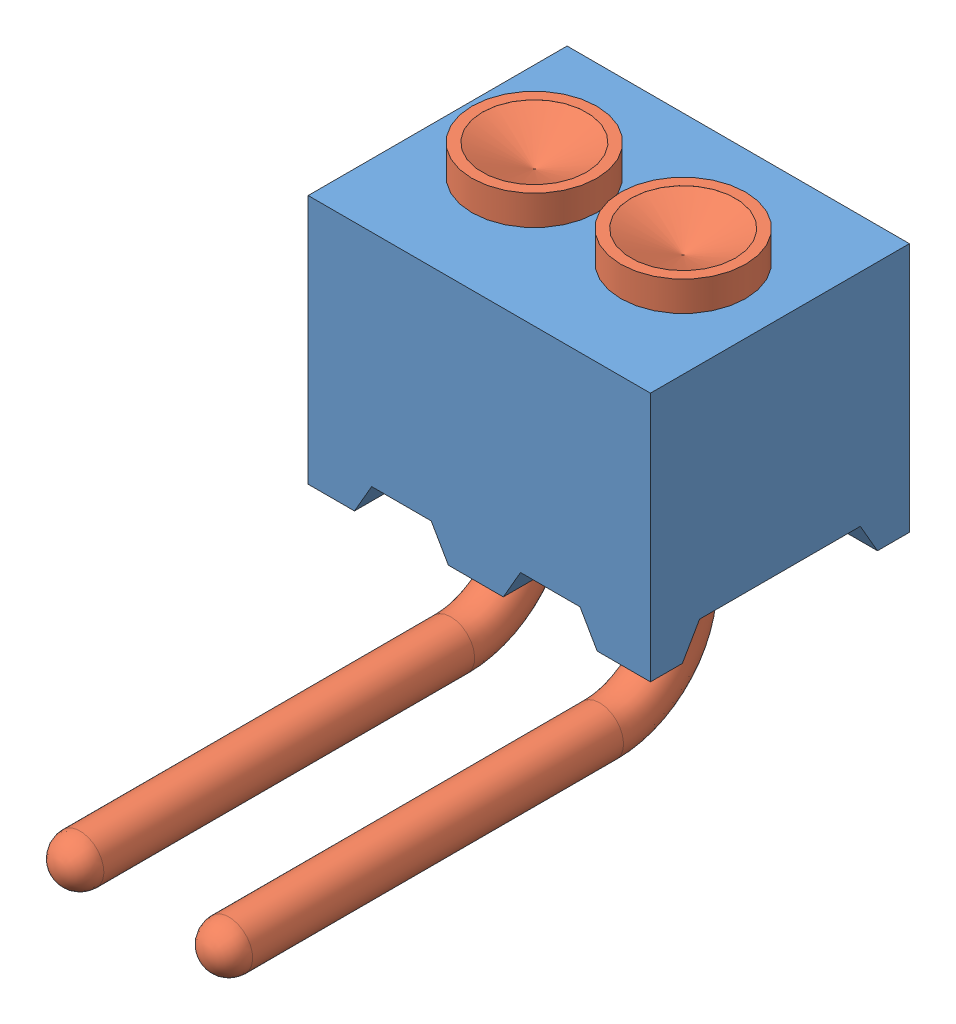
SolidWorks assembly mill-max-856-10-002-20-002000, configuration Default. Lengths in mm.
Overall size (2.92 3.56 5.18).
3 component instances, 2 part files, 0 mates.
Components (placement in the parent):
- mill-max-856-10-002-20-002000_P8XX-18-011-02-000000(P802-18-011-02-000000)-1: mill-max-856-10-002-20-002000_P8XX-18-011-02-000000(P802-18-011-02-000000) [Default] at origin size (2.92 2.13 2.21)
- mill-max-856-10-002-20-002000_1831-1: mill-max-856-10-002-20-002000_1831 [Default] at (2.0955 0.254 -1.1049) x (0 -1 0) z (1 0 0) size (3.56 4.61 1.07)
- mill-max-856-10-002-20-002000_1831-2: mill-max-856-10-002-20-002000_1831 [Default] at (0.8255 0.254 -1.1049) x (0 -1 0) z (1 0 0) size (3.56 4.61 1.07)
